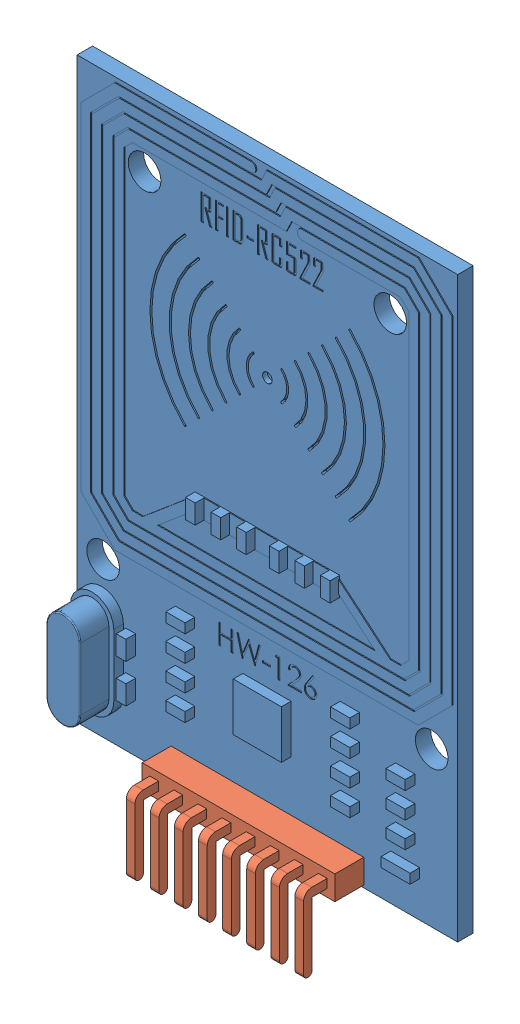
SolidWorks assembly Ensamblaje1, configuration Predeterminado. Lengths in mm.
Overall size (39.5 65.95 8.45).
2 component instances, 2 part files, 3 mates.
Components (placement in the parent):
- TARJETA RFID-1: TARJETA RFID [Predeterminado] at (-35.1098 29.1208 -2.8) size (39.5 60 5.6)
- PINES 90-1: PINES 90 [Predeterminado] at (-35.1098 0.6208 1.8) x (-1 0 0) z (0 0 -1) size (20 8.7 8.45)
Mates (geometry in assembly coordinates):
- Coincidente1: coincident: plane of TARJETA RFID-1 through (-35.1098 29.1208 -1.2) normal (0 0 1); plane of PINES 90-1 through (-34.4425 -2.7309 -1.2) normal (0 0 -1)
- Concéntrica2: concentric: cylinder of TARJETA RFID-1 through (-26.3598 0.6208 -2.8) axis (0 0 1) radius 0.5; cylinder of PINES 90-1 through (-26.3598 0.6208 -4.2) axis (0 0 1) radius 0.4616
- Concéntrica3: concentric aligned: cylinder of TARJETA RFID-1 through (-43.8598 0.6208 -2.8) axis (0 0 1) radius 0.5; cylinder of PINES 90-1 through (-43.8598 0.6208 -4.2) axis (0 0 1) radius 0.4616
